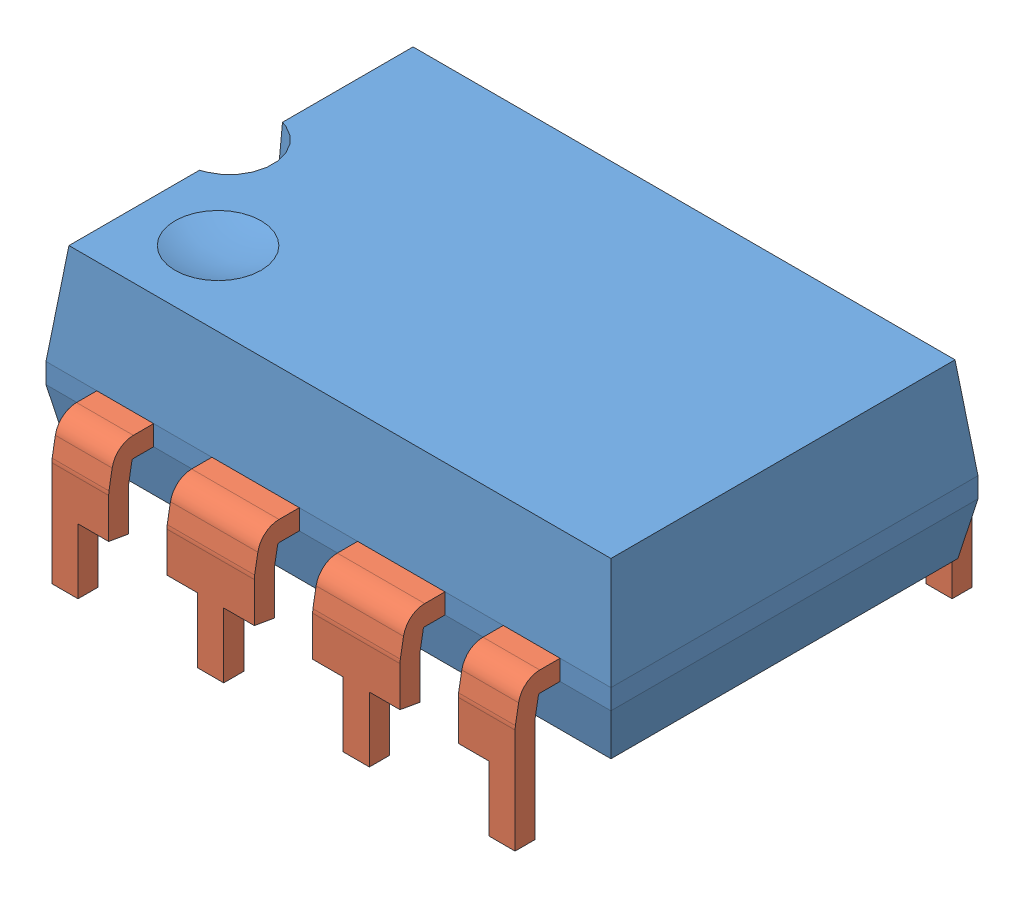
SolidWorks assembly DIP8, configuration Default. Lengths in mm.
Overall size (9.85 4.27 7.97).
3 component instances, 2 part files, 6 mates.
Components (placement in the parent):
- 8DIP_body-1: 8DIP_body [Default] at (-0.3226 0.0308 0.1493) size (9.85 3 6.4)
- 8DIP_pins-1: 8DIP_pins [Default] at (-0.3226 -0.1442 -2.0507) size (8.08 2.52 1.78)
- 8DIP_pins-2: 8DIP_pins [Default] at (-0.3226 -0.1442 2.3493) x (-1 0 0) z (0 0 -1) size (8.08 2.52 1.78)
Mates (geometry in assembly coordinates):
- Coincident1: coincident anti-aligned: plane of 8DIP_pins-2 through (3.716 0.0308 2.3493) normal (0 0 -1); plane of 8DIP_body-1 through (-3.3706 -0.3192 2.3493) normal (0 0 1)
- Coincident2: coincident anti-aligned: plane of 8DIP_body-1 through (-4.3612 0.0308 2.3493) normal (1 0 0); plane of 8DIP_pins-2 through (-4.3612 0.0308 3.7033) normal (-1 0 0)
- Coincident3: coincident anti-aligned: plane of 8DIP_body-1 through (-4.3612 -0.3192 2.3493) normal (0 1 0); plane of 8DIP_pins-2 through (-4.3612 -0.3192 3.7033) normal (0 -1 0)
- Coincident4: coincident anti-aligned: plane of 8DIP_body-1 through (-3.3706 -0.3192 -2.0507) normal (0 0 -1); plane of 8DIP_pins-1 through (-4.3612 0.0308 -2.0507) normal (0 0 1)
- Coincident5: coincident anti-aligned: plane of 8DIP_body-1 through (-4.3612 0.0308 -2.0507) normal (1 0 0); plane of 8DIP_pins-1 through (-4.3612 0.0308 -3.4047) normal (-1 0 0)
- Coincident6: coincident anti-aligned: plane of 8DIP_body-1 through (-4.3612 -0.3192 -2.0507) normal (0 1 0); plane of 8DIP_pins-1 through (-3.3706 -0.3192 -3.4047) normal (0 -1 0); sketch_entity of 8DIP_body-1
